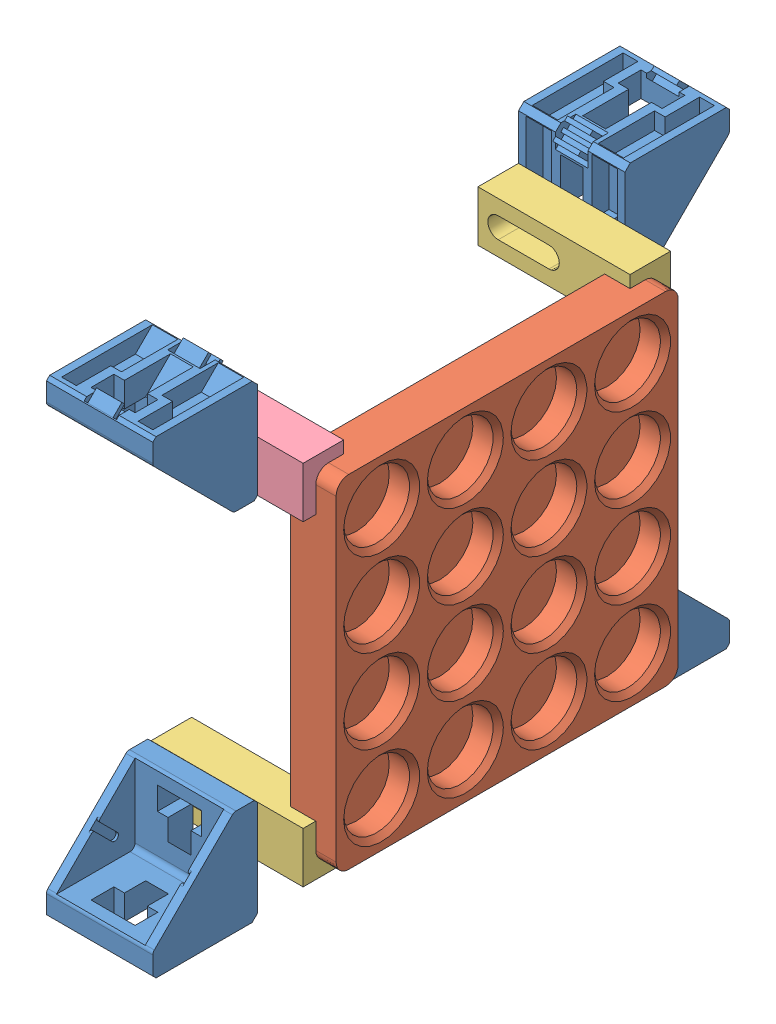
SolidWorks assembly Nosac_Buffera_Sklopni, configuration Default. Lengths in mm.
Overall size (68 189.95 227.6).
9 component instances, 4 part files, 24 mates.
Components (placement in the parent):
- Kutni_Spoj_45x45-1: Kutni_Spoj_45x45 [Default] at (-0.7163 10.3511 18.4877) size (42 43.77 43.77)
- Kutni_Spoj_45x45-2: Kutni_Spoj_45x45 [Default] at (-0.7163 10.3511 -126.5123) x (-1 0 0) z (0 0 -1) size (42 43.77 43.77)
- Kutni_Spoj_45x45-3: Kutni_Spoj_45x45 [Default] at (-0.7163 195.3511 -126.5123) x (-1 0 0) z (0 -1 0) size (42 43.77 43.77)
- Kutni_Spoj_45x45-4: Kutni_Spoj_45x45 [Default] at (-0.7163 195.3511 18.4877) x (1 0 0) z (0 -1 0) size (42 43.77 43.77)
- Pallet-1: Pallet [Default] at (28.2837 102.9511 -54.0123) x (0 -1 0) z (0 0 1) size (135 18 135)
- Nosac_Buffera-1: Nosac_Buffera [Default] at (-21.7163 40.4511 10.4877) x (0 1 0) z (0 0 -1) size (20 60 16)
- Nosac_Buffera-2: Nosac_Buffera [Default] at (-21.7163 165.2511 -118.5123) x (0 -1 0) z (0 0 1) size (20 60 16)
- Nosac_Buffera_2-1: Nosac_Buffera_2 [Default] at (-21.7163 165.2511 10.4877) x (0 -1 0) z (0 0 1) size (20 60 16)
- Nosac_Buffera_2-2: Nosac_Buffera_2 [Default] at (-21.7163 40.4511 -118.5123) x (0 1 0) z (0 0 -1) size (20 60 16)
Mates (geometry in assembly coordinates):
- Distance1: distance = 145 mm anti-aligned: plane of Kutni_Spoj_45x45-1 through (-21.7163 12.4724 18.4877) normal (0 0 -1); plane of Kutni_Spoj_45x45-2 through (20.2837 12.4724 -126.5123) normal (0 0 1)
- Coincident2: coincident anti-aligned: plane of Kutni_Spoj_45x45-1 through (-0.7163 10.3511 18.4877) normal (1 0 0); plane of Kutni_Spoj_45x45-2 through (-0.7163 10.3511 -126.5123) normal (-1 0 0)
- Coincident3: coincident aligned: plane of Kutni_Spoj_45x45-1 through (-0.7163 10.3511 18.4877) normal (0 1 0); plane of Kutni_Spoj_45x45-2 through (-0.7163 10.3511 -126.5123) normal (0 1 0)
- Coincident4: coincident aligned: plane of Kutni_Spoj_45x45-3 through (-0.7163 195.3511 -126.5123) normal (0 -1 0); plane of Kutni_Spoj_45x45-4 through (-0.7163 195.3511 18.4877) normal (0 -1 0)
- Coincident5: coincident anti-aligned: plane of Kutni_Spoj_45x45-3 through (-0.7163 195.3511 -126.5123) normal (-1 0 0); plane of Kutni_Spoj_45x45-4 through (-0.7163 195.3511 18.4877) normal (1 0 0)
- Distance2: distance = 145 mm anti-aligned: plane of Kutni_Spoj_45x45-3 through (-0.7163 195.3511 -126.5123) normal (0 0 -1); plane of Kutni_Spoj_45x45-4 through (-0.7163 195.3511 18.4877) normal (0 0 1)
- Distance3: distance = 185 mm anti-aligned: plane of Kutni_Spoj_45x45-1 through (-0.7163 10.3511 18.4877) normal (0 1 0); plane of Kutni_Spoj_45x45-3 through (-0.7163 195.3511 -126.5123) normal (0 -1 0)
- Coincident8: coincident anti-aligned: plane of Kutni_Spoj_45x45-1 through (-0.7163 10.3511 18.4877) normal (1 0 0); plane of Kutni_Spoj_45x45-3 through (-0.7163 195.3511 -126.5123) normal (-1 0 0)
- Coincident9: coincident aligned: plane of Kutni_Spoj_45x45-1 through (-0.7163 10.3511 18.4877) normal (0 0 1); plane of Kutni_Spoj_45x45-4 through (-0.7163 195.3511 18.4877) normal (0 0 1)
- Coincident10: coincident anti-aligned: plane of Kutni_Spoj_45x45-1 through (-21.7163 12.4724 18.4877) normal (0 0 -1); plane of Nosac_Buffera-1 through (-21.7163 36.6511 18.4877) normal (0 0 1)
- Coincident11: coincident aligned: plane of Kutni_Spoj_45x45-1 through (-21.7163 10.3511 18.4877) normal (-1 0 0); plane of Nosac_Buffera-1 through (-21.7163 26.6511 2.4877) normal (-1 0 0)
- Distance4: distance = 1.2 mm aligned: plane of Nosac_Buffera-1 through (-21.7163 50.4511 2.4877) normal (0 1 0); plane of Kutni_Spoj_45x45-1 through (-21.7163 51.6511 19.7655) normal (0 1 0)
- Coincident13: coincident anti-aligned: plane of Pallet-1 through (28.2837 99.1511 -54.0123) normal (-1 0 0); plane of Nosac_Buffera-1 through (28.2837 36.6511 8.4877) normal (1 0 0)
- Coincident14: coincident anti-aligned: plane of Pallet-1 through (46.2837 31.6511 13.4877) normal (0 -1 0); plane of Nosac_Buffera-1 through (28.2837 31.6511 8.4877) normal (0 1 0)
- Coincident15: coincident anti-aligned: plane of Pallet-1 through (46.2837 166.6511 13.4877) normal (0 0 1); plane of Nosac_Buffera-1 through (28.2837 46.6511 13.4877) normal (0 0 -1)
- Coincident16: coincident anti-aligned: plane of Kutni_Spoj_45x45-3 through (20.2837 155.3289 -126.5123) normal (0 0 1); plane of Nosac_Buffera-2 through (-21.7163 169.0511 -126.5123) normal (0 0 -1)
- Coincident17: coincident aligned: plane of Kutni_Spoj_45x45-3 through (-21.7163 195.3511 -126.5123) normal (-1 0 0); plane of Nosac_Buffera-2 through (-21.7163 179.0511 -110.5123) normal (-1 0 0)
- Distance5: distance = 1.2 mm aligned: plane of Nosac_Buffera-2 through (-21.7163 155.2511 -110.5123) normal (0 -1 0); plane of Kutni_Spoj_45x45-3 through (20.2837 154.0511 -135.0127) normal (0 -1 0)
- Coincident19: coincident anti-aligned: plane of Kutni_Spoj_45x45-4 through (-21.7163 155.3289 18.4877) normal (0 0 -1); plane of Nosac_Buffera_2-1 through (-21.7163 165.2511 18.4877) normal (0 0 1)
- Coincident20: coincident aligned: plane of Kutni_Spoj_45x45-4 through (-21.7163 195.3511 18.4877) normal (-1 0 0); plane of Nosac_Buffera_2-1 through (-21.7163 175.2511 18.4877) normal (-1 0 0)
- Distance6: distance = 1.2 mm aligned: plane of Nosac_Buffera_2-1 through (-21.7163 155.2511 18.4877) normal (0 -1 0); plane of Kutni_Spoj_45x45-4 through (-21.7163 154.0511 26.9881) normal (0 -1 0)
- Coincident22: coincident anti-aligned: plane of Kutni_Spoj_45x45-2 through (20.2837 12.4724 -126.5123) normal (0 0 1); plane of Nosac_Buffera_2-2 through (-21.7163 40.6511 -126.5123) normal (0 0 -1)
- Coincident23: coincident aligned: plane of Kutni_Spoj_45x45-2 through (-21.7163 10.3511 -126.5123) normal (-1 0 0); plane of Nosac_Buffera_2-2 through (-21.7163 30.6511 -126.5123) normal (-1 0 0)
- Distance7: distance = 1.2 mm aligned: plane of Nosac_Buffera_2-2 through (-21.7163 50.4511 -126.5123) normal (0 1 0); plane of Kutni_Spoj_45x45-2 through (20.2837 51.6511 -127.79) normal (0 1 0)
